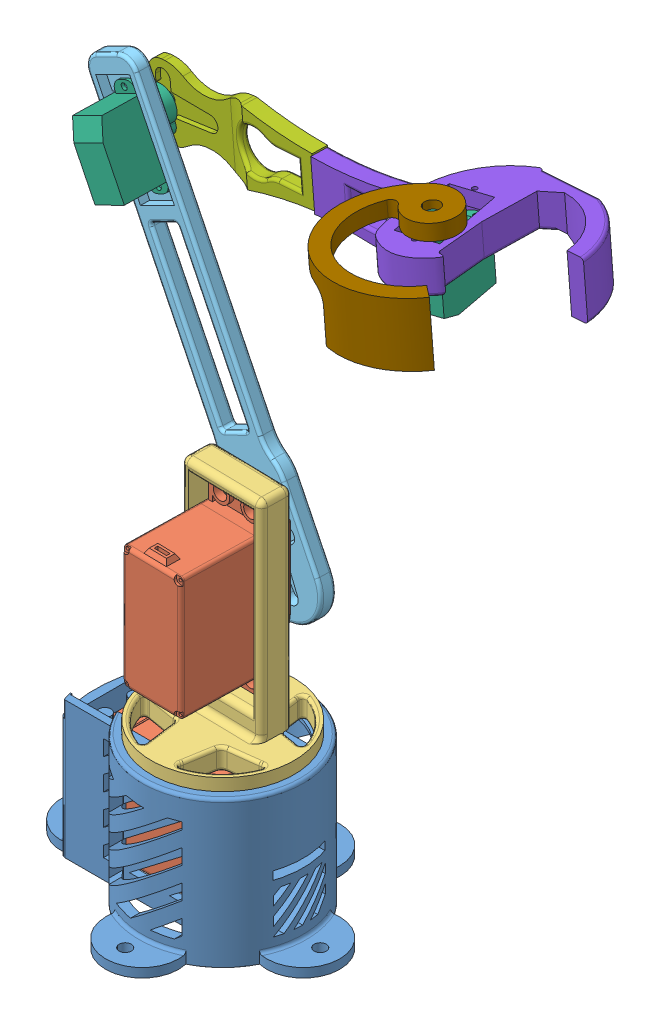
SolidWorks assembly Assembly, configuration Default. Lengths in mm.
Overall size (159.47 217.02 91.17).
11 component instances, 9 part files, 26 mates.
Components (placement in the parent):
- 1-BASE-1: 1-BASE [Default] at (43.5415 4.0704 70.5162) size (91.5 48.07 77)
- BigServo-1: BigServo [Default] at (33.9115 26.6404 70.5962) size (55 43.2 19.81)
- 2-BaseArm-1: 2-BaseArm [Default] at (44.0471 106.1354 60.9995) x (0.999794 0 0.02032) z (-0.02032 0 0.999794) size (47 75.5 47)
- BigServo-2: BigServo [Default] at (43.0746 109.4904 93.4865) x (0 1 0) z (-0.999794 0 -0.02032) size (55 43.2 19.81)
- BigHorn-1: BigHorn [Default] at (43.7234 69.8854 80.7645) x (0.017743 0 0.999843) z (0 1 0) size (39 39 5.5)
- 3-SecondArm-1: 3-SecondArm [Default] at (11.1088 185.6892 49.6279) x (-0.451959 0.891992 -0.009186) z (0.891807 0.452052 0.018125) size (145.37 5 24)
- S3114_servo_CAD_Model-1: S3114_servo_CAD_Model [Default] at (-3.6082 212.4364 52.3294) x (0.891807 0.452052 0.018125) z (-0.451959 0.891992 -0.009186) size (11 26.09 29)
- 4-GripArm 2nd half-1: 4-GripArm 2nd half [Default] at (-3.4773 212.4364 45.8867) x (0.996108 0.085779 0.020245) z (-0.085762 0.996314 -0.001743) size (83.21 5.46 23)
- 4-GripArm 1st half-2: 4-GripArm 1st half [Default] at (-3.4216 211.9384 45.3877) x (0.996108 0.085779 0.020245) z (-0.085762 0.996314 -0.001743) size (84.45 51.17 20.28)
- S3114_servo_CAD_Model-2: S3114_servo_CAD_Model [Default] at (95.1855 222.766 52.2251) x (0.975743 0.083637 -0.202313) z (0.201422 0.019051 0.979319) size (11 26.09 29)
- 5-Gripper-1: 5-Gripper [Default] at (102.4133 236.861 65.516) x (0.531944 0.047268 0.845459) z (0.842426 0.071581 -0.534037) size (50.7 20 33.82)
Mates (geometry in assembly coordinates):
- Concentric1: concentric: cylinder of 1-BASE-1 through (9.7815 66.8772 65.5162) axis (0 -1 0) radius 2; cylinder of BigServo-1 through (9.7815 56.1404 65.5162) axis (0 -1 0) radius 2.25
- Concentric2: concentric: circle of 1-BASE-1; cylinder of BigServo-1 through (58.0415 56.1404 65.5162) axis (0 -1 0) radius 2.25
- Coincident1: coincident: plane of 1-BASE-1 through (43.5415 53.6404 70.5162) normal (0 1 0); plane of BigServo-1 through (59.9115 53.6404 77.9962) normal (0 -1 0)
- Concentric3: concentric: cylinder of 2-BaseArm-1 through (49.098 133.6204 47.124) axis (-0.02032 0 0.999794) radius 2; cylinder of BigServo-2 through (48.753 133.6204 64.0958) axis (-0.02032 0 0.999794) radius 2.25
- Concentric4: concentric: cylinder of 2-BaseArm-1 through (39.0483 133.6204 41.5899) axis (-0.02032 0 0.999794) radius 2; cylinder of BigServo-2 through (38.5951 133.6204 63.8893) axis (-0.02032 0 0.999794) radius 2.25
- Coincident2: coincident: plane of 2-BaseArm-1 through (43.9862 106.1354 63.9989) normal (-0.02032 0 0.999794); plane of BigServo-2 through (36.2756 135.4904 63.8422) normal (0.02032 0 -0.999794)
- Concentric5: concentric: circle of 2-BaseArm-1; cylinder of BigHorn-1 through (43.5415 69.9454 70.5162) axis (0 -1 0) radius 3
- Parallel4: parallel: plane of 2-BaseArm-1 through (37.9102 71.6354 74.6815) normal (0.165068 0 -0.986282); plane of BigHorn-1 through (44.5024 69.8854 76.1095) normal (-0.165068 0 0.986282)
- Coincident6: coincident: plane of 2-BaseArm-1 through (37.6626 71.6354 76.1609) normal (0 -1 0); plane of BigHorn-1 through (43.7234 71.6354 80.7645) normal (0 1 0)
- Concentric10: concentric: cylinder of 1-BASE-1 through (43.5415 -51.7953 70.5162) axis (0 1 0) radius 23.5; cylinder of BigHorn-1 through (43.5415 69.9454 70.5162) axis (0 -1 0) radius 3
- Coincident7: coincident: plane of 1-BASE-1 through (43.5415 66.6354 70.5162) normal (0 1 0); plane of 2-BaseArm-1 through (43.5415 66.6354 70.5162) normal (0 -1 0)
- Concentric11: concentric: circle of BigServo-2; circle of 3-SecondArm-1
- Coincident10: coincident: plane of BigServo-2 through (43.8509 118.6904 55.2943) normal (0.02032 0 -0.999794); plane of 3-SecondArm-1 through (43.8509 118.6904 55.2943) normal (-0.02032 0 0.999794)
- Concentric12: concentric: cylinder of 3-SecondArm-1 through (-7.0726 219.394 49.2583) axis (-0.02032 0 0.999794) radius 1; cylinder of S3114_servo_CAD_Model-1 through (-7.1335 219.394 52.2577) axis (0.02032 0 -0.999794) radius 1
- Concentric13: concentric: cylinder of 3-SecondArm-1 through (4.4072 196.7374 49.4917) axis (-0.02032 0 0.999794) radius 1; cylinder of S3114_servo_CAD_Model-1 through (4.3462 196.7374 52.491) axis (0.02032 0 -0.999794) radius 1
- Coincident14: coincident: plane of 3-SecondArm-1 through (11.0682 185.6892 51.6274) normal (-0.02032 0 0.999794); plane of S3114_servo_CAD_Model-1 through (-3.5879 212.4364 51.3296) normal (0.02032 0 -0.999794)
- Concentric15: concentric: cylinder of S3114_servo_CAD_Model-1 through (-3.4375 212.4364 43.9311) axis (0.02032 0 -0.999794) radius 1.9368; cylinder of 4-GripArm 2nd half-1 through (-3.8926 212.4364 66.3193) axis (0.02032 0 -0.999794) radius 0.75
- Coincident23: coincident: plane of S3114_servo_CAD_Model-1 through (-3.3808 212.4364 41.1377) normal (0.02032 0 -0.999794); plane of 4-GripArm 2nd half-1 through (-3.9382 218.9125 41.1264) normal (-0.02032 0 0.999794)
- Concentric16: concentric: cylinder of 4-GripArm 1st half-2 through (95.5833 236.5451 59.8399) axis (0.085762 -0.996314 0.001743) radius 0.8; cylinder of S3114_servo_CAD_Model-2 through (96.7566 222.9146 59.8638) axis (-0.085762 0.996314 -0.001743) radius 1
- Concentric17: concentric: cylinder of 4-GripArm 1st half-2 through (90.4672 236.0612 34.9652) axis (0.085762 -0.996314 0.001743) radius 0.8; cylinder of S3114_servo_CAD_Model-2 through (91.6405 222.4307 34.9891) axis (-0.085762 0.996314 -0.001743) radius 1
- Coincident33: coincident: plane of 4-GripArm 2nd half-1 through (59.5358 211.9205 45.167) normal (-0.02032 0 0.999794); plane of 4-GripArm 1st half-2 through (58.5209 223.7107 45.1463) normal (0.02032 0 -0.999794)
- Coincident34: coincident: plane of 4-GripArm 2nd half-1 through (58.9877 217.8156 47.1562) normal (0.996108 0.085779 0.020245); plane of 4-GripArm 1st half-2 through (59.0408 217.3173 46.6572) normal (-0.996108 -0.085779 -0.020245)
- Coincident35: coincident: plane of 4-GripArm 2nd half-1 through (58.5209 223.7107 45.1463) normal (-0.085762 0.996314 -0.001743); plane of 4-GripArm 1st half-2 through (58.5819 223.7107 42.147) normal (0.085762 -0.996314 0.001743)
- Concentric18: concentric: cylinder of S3114_servo_CAD_Model-2 through (94.4651 231.135 52.2104) axis (-0.085762 0.996314 -0.001743) radius 1.9368; cylinder of 5-Gripper-1 through (94.4651 231.135 52.2104) axis (-0.085762 0.996314 -0.001743) radius 2.5
- Coincident36: coincident: plane of S3114_servo_CAD_Model-2 through (94.4651 231.135 52.2104) normal (-0.085762 0.996314 -0.001743); plane of 5-Gripper-1 through (102.8422 231.8794 65.5247) normal (0.085762 -0.996314 0.001743)
- Coincident37: coincident: plane of 4-GripArm 1st half-2 through (106.5433 232.2056 69.8522) normal (-0.085762 0.996314 -0.001743); plane of 5-Gripper-1 through (102.8422 231.8794 65.5247) normal (0.085762 -0.996314 0.001743)
